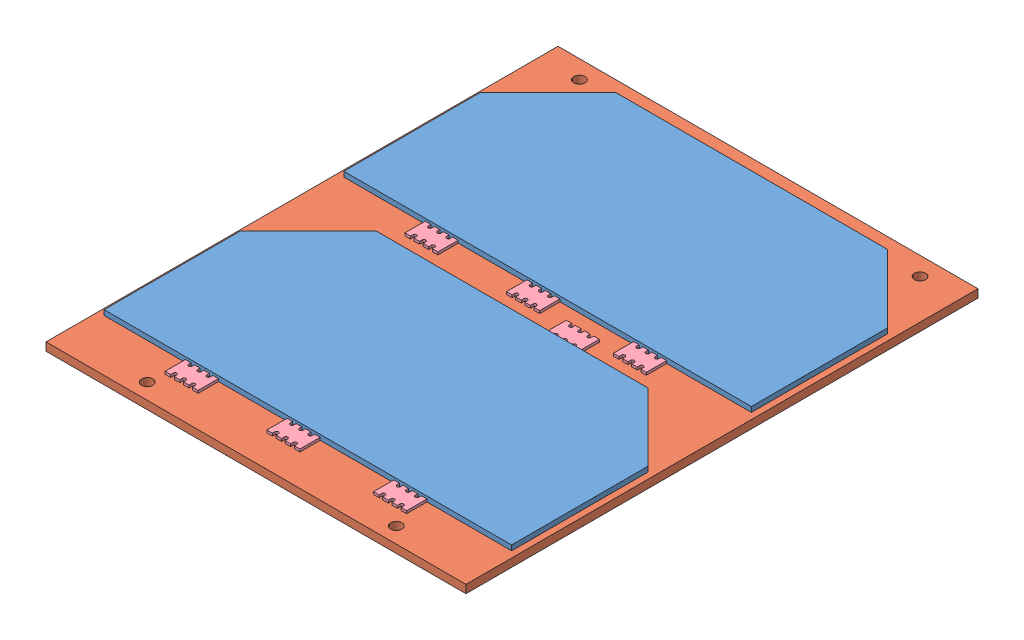
SolidWorks assembly B3_+Y_panel, configuration Default. Lengths in mm.
Overall size (82.6 7.1 100.7).
11 component instances, 4 part files, 29 mates.
Components (placement in the parent):
- Solar panel-1: Solar panel [Default] at (-43.4703 -35.5175 64.7205) size (80.15 1 40.15)
- Solar panel-2: Solar panel [Default] at (-69.4046 -34.5175 111.8705) x (-1 0 0) z (0 0 1) size (80.15 1 40.15)
- B3_±Y_panel-2: B3_±Y_panel [Default] at (-32.6974 -37.1175 99.3411) x (-1 0 0) z (0 0 -1) size (82.6 1.6 100.7)
- Solar panel_f-1: Solar panel_f [Default] at (-68.4374 -41.6175 123.2036) x (0 0 -1) z (-1 0 0) size (3.7 4.5 24)
- Solar panel_connector-1: Solar panel_connector [Default] at (-74.0124 -35.5175 74.5536) size (6.5 0.5 4)
- Solar panel_connector-2: Solar panel_connector [Default] at (-74.0124 -35.5175 121.7036) size (6.5 0.5 4)
- Solar panel_connector-3: Solar panel_connector [Default] at (-54.0124 -35.5175 121.7036) size (6.5 0.5 4)
- Solar panel_connector-4: Solar panel_connector [Default] at (-33.0124 -35.5175 121.7036) size (6.5 0.5 4)
- Solar panel_connector-5: Solar panel_connector [Default] at (-33.0124 -35.5175 74.5536) size (6.5 0.5 4)
- Solar panel_connector-6: Solar panel_connector [Default] at (-54.0124 -35.5175 74.5536) size (6.5 0.5 4)
- Solar panel_connector-7: Solar panel_connector [Default] at (-43.2624 -35.5175 77.5536) size (6.5 0.5 4)
Mates (geometry in assembly coordinates):
- Coincident1: coincident aligned: plane of Solar panel-1 through (-43.4703 -34.5175 64.7205) normal (0 1 0); plane of Solar panel-2 through (-69.4046 -34.5175 111.8705) normal (0 1 0)
- Coincident25: coincident anti-aligned: plane of Solar panel-1 through (-43.4703 -35.5175 64.7205) normal (0 -1 0); plane of B3_±Y_panel-2 through (-32.6974 -35.5175 99.3411) normal (0 1 0)
- Coincident26: coincident anti-aligned: plane of B3_±Y_panel-2 through (-32.6974 -37.1175 99.3411) normal (0 -1 0); plane of Solar panel_f-1 through (-68.4374 -37.1175 123.2036) normal (0 1 0)
- Coincident34: coincident aligned: plane of Solar panel-1 through (-96.5124 -34.5175 74.5536) normal (-1 0 0); plane of Solar panel-2 through (-96.5124 -35.5175 94.9036) normal (-1 0 0)
- Distance9: distance = 8.7 mm aligned: plane of Solar panel_f-1 through (-44.4374 -41.6175 123.2036) normal (0 0 1); plane of B3_±Y_panel-2 through (-14.9374 -35.5175 131.9036) normal (0 0 1)
- Distance12: distance = 1.225 mm aligned: plane of Solar panel-1 through (-96.5124 -34.5175 74.5536) normal (-1 0 0); plane of B3_±Y_panel-2 through (-97.7374 -35.5175 31.2036) normal (-1 0 0)
- Distance13: distance = 29.3 mm aligned: plane of Solar panel_f-1 through (-68.4374 -41.6175 123.2036) normal (-1 0 0); plane of B3_±Y_panel-2 through (-97.7374 -35.5175 31.2036) normal (-1 0 0)
- Distance15: distance = 3.2 mm aligned: plane of Solar panel-1 through (-83.1624 -34.5175 34.4036) normal (0 0 -1); plane of B3_±Y_panel-2 through (-97.9374 -35.5175 31.2036) normal (0 0 -1)
- 一致1: coincident anti-aligned: plane of B3_±Y_panel-2 through (-32.6974 -35.5175 99.3411) normal (0 1 0); plane of Solar panel_connector-1 through (-75.4624 -35.5175 78.0536) normal (0 -1 0)
- 一致2: coincident anti-aligned: plane of B3_±Y_panel-2 through (-32.6974 -35.5175 99.3411) normal (0 1 0); plane of Solar panel_connector-7 through (-44.7124 -35.5175 81.0536) normal (0 -1 0)
- 一致3: coincident anti-aligned: plane of B3_±Y_panel-2 through (-32.6974 -35.5175 99.3411) normal (0 1 0); plane of Solar panel_connector-6 through (-55.4624 -35.5175 78.0536) normal (0 -1 0)
- 一致4: coincident anti-aligned: plane of B3_±Y_panel-2 through (-32.6974 -35.5175 99.3411) normal (0 1 0); plane of Solar panel_connector-5 through (-34.4624 -35.5175 78.0536) normal (0 -1 0)
- 一致5: coincident anti-aligned: plane of B3_±Y_panel-2 through (-32.6974 -35.5175 99.3411) normal (0 1 0); plane of Solar panel_connector-4 through (-34.4624 -35.5175 125.2036) normal (0 -1 0)
- 一致9: coincident anti-aligned: plane of B3_±Y_panel-2 through (-32.6974 -35.5175 99.3411) normal (0 1 0); plane of Solar panel_connector-3 through (-55.4624 -35.5175 125.2036) normal (0 -1 0)
- 一致10: coincident anti-aligned: plane of B3_±Y_panel-2 through (-32.6974 -35.5175 99.3411) normal (0 1 0); plane of Solar panel_connector-2 through (-75.4624 -35.5175 125.2036) normal (0 -1 0)
- 距離1: distance = 16 mm: plane of Solar panel-1 through (-96.5124 -34.5175 74.5536) normal (-1 0 0); line of Solar panel_connector-1 through (-80.5124 -35.0175 74.5536) axis (0 0 1)
- 一致14: coincident anti-aligned: plane of Solar panel-1 through (-16.3624 -34.5175 74.5536) normal (0 0 1); plane of Solar panel_connector-1 through (-77.6124 -35.0175 74.5536) normal (0 0 -1)
- 距離2: distance = 36 mm: line of Solar panel-1 through (-96.5124 -34.5175 47.7536) axis (0 0 1); plane of Solar panel_connector-6 through (-60.5124 -35.0175 74.5536) normal (-1 0 0)
- 一致16: coincident anti-aligned: plane of Solar panel-1 through (-16.3624 -34.5175 74.5536) normal (0 0 1); plane of Solar panel_connector-6 through (-57.6124 -35.0175 74.5536) normal (0 0 -1)
- 距離4: distance = 57 mm aligned: plane of Solar panel-1 through (-96.5124 -34.5175 74.5536) normal (-1 0 0); plane of Solar panel_connector-5 through (-39.5124 -35.0175 74.5536) normal (-1 0 0)
- 一致21: coincident anti-aligned: plane of Solar panel-1 through (-16.3624 -34.5175 74.5536) normal (0 0 1); plane of Solar panel_connector-5 through (-35.9124 -35.0175 74.5536) normal (0 0 -1)
- 一致23: coincident aligned: line of Solar panel_connector-1 through (-80.5124 -35.0175 74.5536) axis (0 0 1); line of Solar panel_connector-2 through (-80.5124 -35.0175 121.7036) axis (0 0 1)
- 一致24: coincident anti-aligned: plane of Solar panel-2 through (-96.5124 -35.5175 121.7036) normal (0 0 1); plane of Solar panel_connector-2 through (-76.9124 -35.0175 121.7036) normal (0 0 -1)
- 一致25: coincident aligned: line of Solar panel_connector-3 through (-60.5124 -35.0175 121.7036) axis (0 0 1); line of Solar panel_connector-6 through (-60.5124 -35.0175 74.5536) axis (0 0 1)
- 一致26: coincident anti-aligned: plane of Solar panel-2 through (-96.5124 -35.5175 121.7036) normal (0 0 1); plane of Solar panel_connector-3 through (-56.9124 -35.0175 121.7036) normal (0 0 -1)
- 一致27: coincident: line of Solar panel_connector-4 through (-39.5124 -35.0175 121.7036) axis (0 0 1); plane of Solar panel_connector-5 through (-39.5124 -35.0175 74.5536) normal (-1 0 0)
- 一致28: coincident anti-aligned: plane of Solar panel-2 through (-96.5124 -35.5175 121.7036) normal (0 0 1); plane of Solar panel_connector-4 through (-35.9124 -35.0175 121.7036) normal (0 0 -1)
- 一致29: coincident anti-aligned: plane of Solar panel-2 through (-29.7124 -35.5175 81.5536) normal (0 0 -1); plane of Solar panel_connector-7 through (-48.6624 -35.0175 81.5536) normal (0 0 1)
- 距離5: distance = 46.75 mm: line of Solar panel_connector-7 through (-49.7624 -35.0175 77.5536) axis (0 0 1); plane of Solar panel-2 through (-96.5124 -35.5175 94.9036) normal (-1 0 0)
